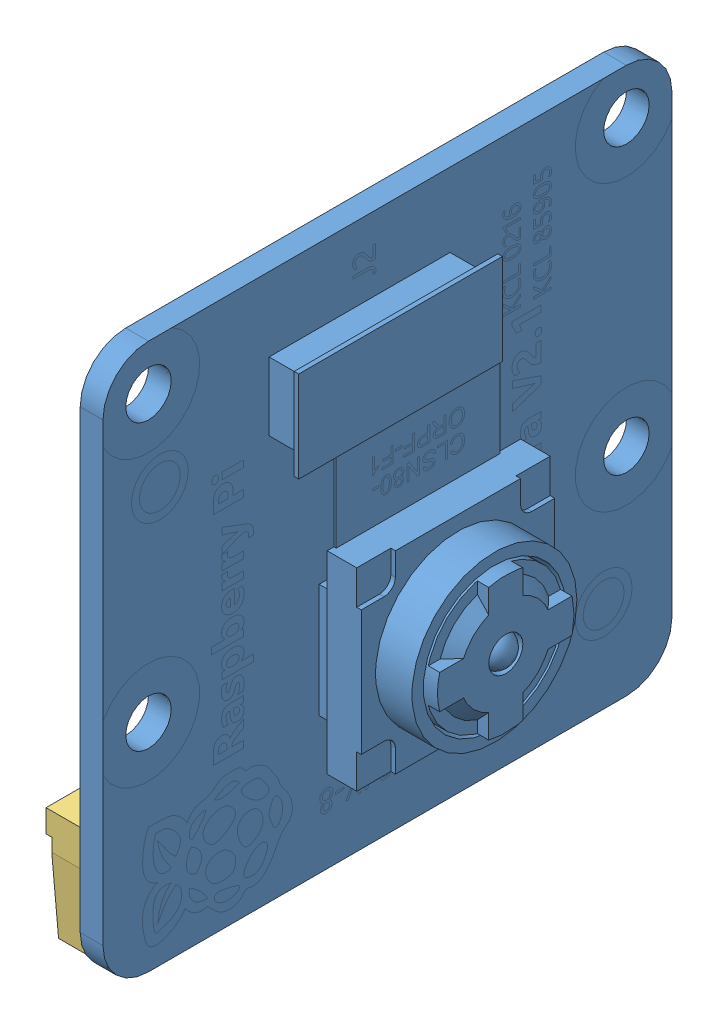
SolidWorks assembly Raspberry pi 3 cam V2,1, configuration Default. Lengths in mm.
Overall size (8.95 26 25).
4 component instances, 3 part files, 4 mates.
Components (placement in the parent):
- Cam V2.1 v1-1: Cam V2.1 v1 [Default] at (-33.079 23.9126 -0.4923) size (6.45 24 25)
- 15 Pin Ribbon Block Assem-1: 15 Pin Ribbon Block Assem [Default] at (-45.1487 -2.7827 -8.2093) x (0 0 1) z (0 1 0) size (22 2.5 7)
  - 15 Pin Ribbon Block-1: 15 Pin Ribbon Block [Default] at (8.217 10.8197 14.6952) size (20 2.5 6)
  - Ribbon Clamp-1: Ribbon Clamp [Default] at (8.217 10.8197 14.6952) size (22 2.5 5)
Mates (geometry in assembly coordinates):
- Coincident3: coincident aligned: plane of Cam V2.1 v1-1 through (-33.079 11.9126 10.0077) normal (0 -1 0); plane of 15 Pin Ribbon Block Assem-1/15 Pin Ribbon Block-1 through (-34.329 6.9126 0.0077) normal (0 -1 0)
- Parallel2: parallel anti-aligned: line of Cam V2.1 v1-1 through (-32.079 11.9126 10.0077) axis (0 0 -1); line of 15 Pin Ribbon Block Assem-1/15 Pin Ribbon Block-1 through (-33.179 6.9126 -9.9923) axis (0 0 1)
- Coincident5: coincident anti-aligned: plane of Cam V2.1 v1-1 through (-33.079 23.9126 -0.4923) normal (-1 0 0); plane of 15 Pin Ribbon Block Assem-1/Ribbon Clamp-1 through (-33.079 11.9126 -10.9923) normal (1 0 0)
- Coincident6: coincident: line of Cam V2.1 v1-1 through (-33.079 11.9126 -10.9923) axis (1 0 0); plane of 15 Pin Ribbon Block Assem-1/Ribbon Clamp-1 through (-33.079 11.9126 -10.9923) normal (0 0 -1)
